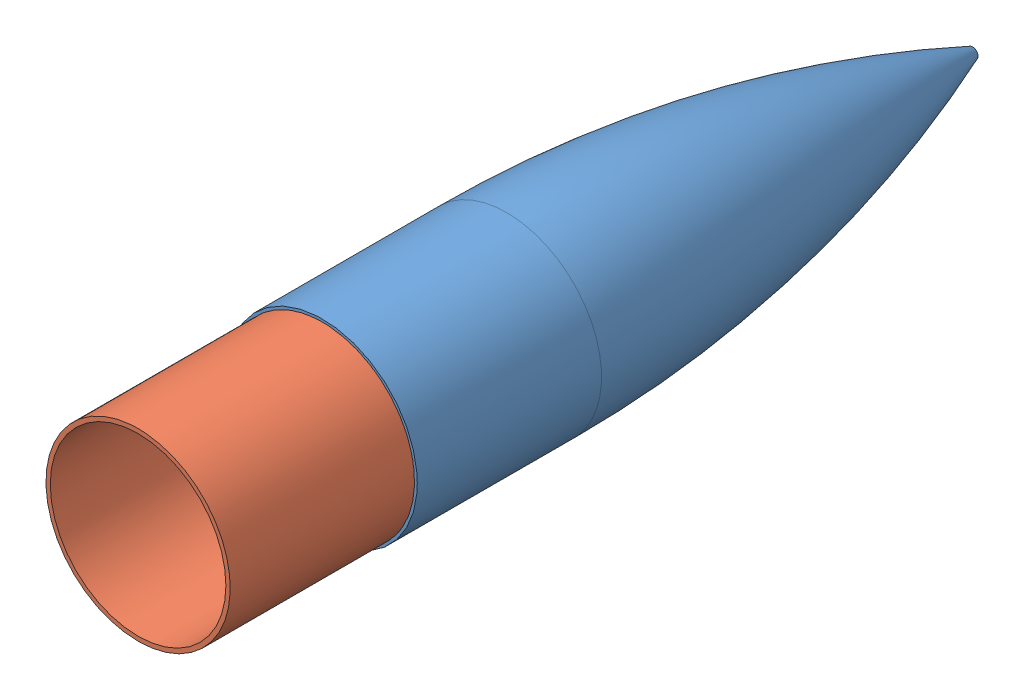
SolidWorks assembly nose_assembly, configuration Default. Lengths in mm.
Overall size (130.81 130.81 575.14).
3 component instances, 3 part files, 5 mates.
Components (placement in the parent):
- MRL_Pitot_Nose_Cone-1: MRL_Pitot_Nose_Cone [Default] at (148.5758 282.8079 519.278) size (130.81 130.81 448.14)
- Coupler(10in)-Nose-1: Coupler(10in)-Nose [Default] at (148.5758 282.8079 671.678) x (1 0 0) z (0 1 0) size (127 254 127)
- 5058K622_ALUMINUM BARBED TUBE FITTING-1: 5058K622_ALUMINUM BARBED TUBE FITTING [5058K622] at (148.5758 282.8079 120.7286) x (0 0 1) z (-1 0 0) size (17.82 11 9.53)
Mates (geometry in assembly coordinates):
- Concentric1: concentric anti-aligned: cylinder of MRL_Pitot_Nose_Cone-1 through (148.5758 282.8079 417.678) axis (0 0 1) radius 63.5; circle of Coupler(10in)-Nose-1
- Coincident2: coincident anti-aligned: plane of MRL_Pitot_Nose_Cone-1 through (148.5758 282.8079 417.678) normal (0 0 1); plane of Coupler(10in)-Nose-1 through (148.5758 282.8079 417.678) normal (0 0 -1)
- Concentric2: concentric anti-aligned: circle of MRL_Pitot_Nose_Cone-1; circle of 5058K622_ALUMINUM BARBED TUBE FITTING-1
- Parallel1: parallel anti-aligned: plane of MRL_Pitot_Nose_Cone-1 through (143.3133 285.8462 417.678) normal (1 0 0); plane of 5058K622_ALUMINUM BARBED TUBE FITTING-1 through (143.8133 285.5575 121.5223) normal (-1 0 0)
- Coincident4: coincident anti-aligned: plane of MRL_Pitot_Nose_Cone-1 through (148.5758 282.8079 111.9973) normal (0 0 1); plane of 5058K622_ALUMINUM BARBED TUBE FITTING-1 through (143.8133 291.0568 111.9973) normal (0 0 -1)
